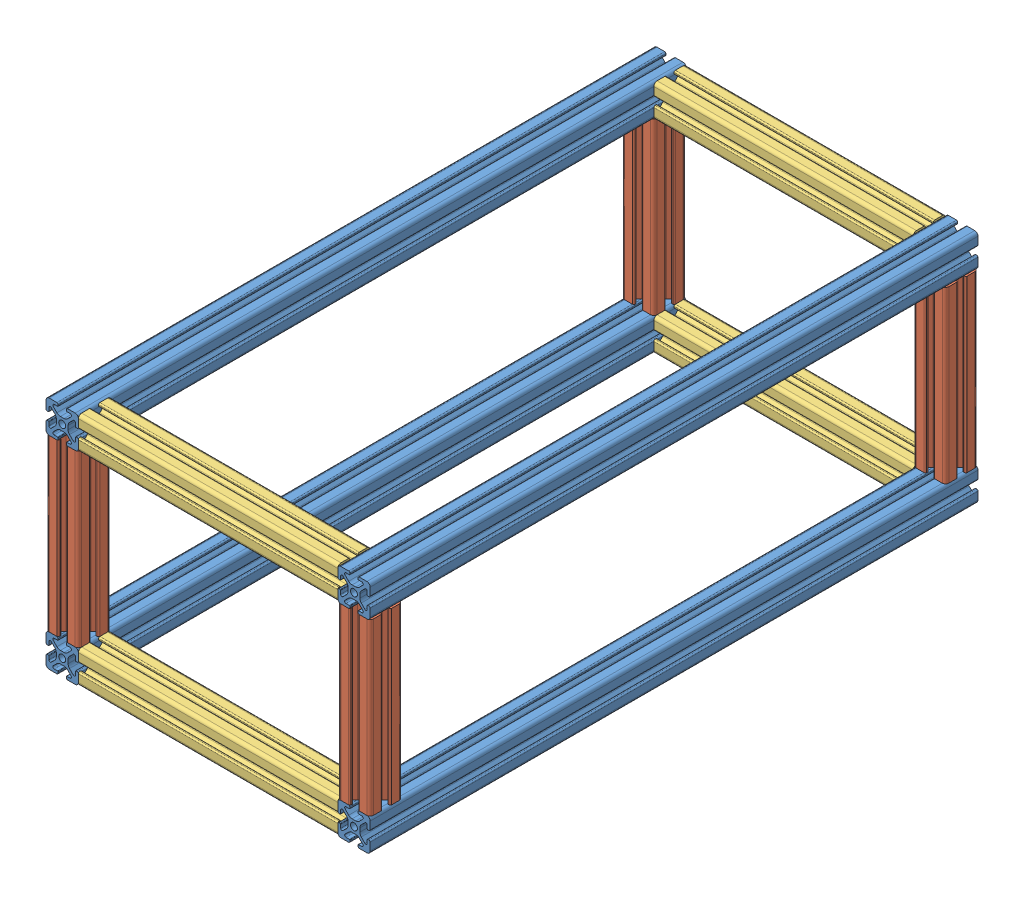
SolidWorks assembly UOR23-LYF-1-A-001, configuration Default. Lengths in mm.
Overall size (199.98 144.98 375).
12 component instances, 3 part files, 39 mates.
Components (placement in the parent):
- UOR23-LYF-1-P-001-8: UOR23-LYF-1-P-001 [Default] at (-89.9949 -62.4949 0) size (19.99 19.99 375)
- UOR23-LYF-1-P-001-9: UOR23-LYF-1-P-001 [Default] at (-89.9949 62.4949 0) size (19.99 19.99 375)
- UOR23-LYF-1-P-002-1: UOR23-LYF-1-P-002 [Default] at (-89.9949 0 177.5051) x (1 0 0) z (0 -1 0) size (19.99 19.99 105)
- UOR23-LYF-1-P-003-1: UOR23-LYF-1-P-003 [Default] at (0 -62.4949 177.5051) x (0 0 1) z (-1 0 0) size (19.99 19.99 160)
- UOR23-LYF-1-P-003-4: UOR23-LYF-1-P-003 [Default] at (0 -62.4949 -177.5051) x (0 0 -1) z (1 0 0) size (19.99 19.99 160)
- UOR23-LYF-1-P-002-2: UOR23-LYF-1-P-002 [Default] at (-89.9949 0 -177.5051) x (1 0 0) z (0 1 0) size (19.99 19.99 105)
- UOR23-LYF-1-P-002-3: UOR23-LYF-1-P-002 [Default] at (89.9949 0 -177.5051) x (-1 0 0) z (0 -1 0) size (19.99 19.99 105)
- UOR23-LYF-1-P-001-10: UOR23-LYF-1-P-001 [Default] at (89.9949 62.4949 0) x (-1 0 0) z (0 0 -1) size (19.99 19.99 375)
- UOR23-LYF-1-P-002-4: UOR23-LYF-1-P-002 [Default] at (89.9949 0 177.5051) x (-1 0 0) z (0 1 0) size (19.99 19.99 105)
- UOR23-LYF-1-P-001-11: UOR23-LYF-1-P-001 [Default] at (89.9949 -62.4949 0) x (-1 0 0) z (0 0 -1) size (19.99 19.99 375)
- UOR23-LYF-1-P-003-6: UOR23-LYF-1-P-003 [Default] at (0 62.4949 177.5051) x (0 1 0) z (1 0 0) size (19.99 19.99 160)
- UOR23-LYF-1-P-003-7: UOR23-LYF-1-P-003 [Default] at (0 62.4949 -177.5051) x (0 0 -1) z (1 0 0) size (19.99 19.99 160)
Mates (geometry in assembly coordinates):
- Coincident1: coincident anti-aligned: plane of UOR22-ARM-3-P-001-4 through (-97.9832 -52.5 187.5) normal (0 1 0); plane of UOR22-ARM-3-P-002-1 through (-91.1283 -52.5 184.1302) normal (0 -1 0)
- Coincident2: coincident aligned: plane of UOR22-ARM-3-P-001-4 through (-91.1283 -55.8698 187.5) normal (0 0 1); plane of UOR22-ARM-3-P-002-1 through (-82.0066 -52.5 187.5) normal (0 0 1)
- Coincident3: coincident aligned: plane of UOR22-ARM-3-P-001-4 through (-80 -54.5066 187.5) normal (1 0 0); plane of UOR22-ARM-3-P-002-1 through (-80 -52.5 185.4934) normal (1 0 0)
- Coincident4: coincident anti-aligned: plane of UOR22-ARM-3-P-001-4 through (-80 -70.4832 187.5) normal (1 0 0); plane of UOR22-ARM-3-P-003-1 through (-80 -55.8698 176.3717) normal (-1 0 0)
- Coincident5: coincident aligned: plane of UOR22-ARM-3-P-001-4 through (-91.1283 -55.8698 187.5) normal (0 0 1); plane of UOR22-ARM-3-P-003-1 through (-80 -70.4832 187.5) normal (0 0 1)
- Coincident6: coincident aligned: plane of UOR22-ARM-3-P-001-4 through (-82.0066 -72.4898 187.5) normal (0 -1 0); plane of UOR22-ARM-3-P-003-1 through (-80 -72.4898 185.4934) normal (0 -1 0)
- Coincident10: coincident aligned: plane of UOR22-ARM-3-P-001-7 through (-91.1283 69.12 187.5) normal (0 0 1); plane of UOR22-ARM-3-P-002-1 through (-97.9832 -52.5 187.5) normal (0 0 1)
- Coincident11: coincident anti-aligned: plane of UOR22-ARM-3-P-001-7 through (-97.9832 52.5 187.5) normal (0 -1 0); plane of UOR22-ARM-3-P-002-1 through (-91.1283 52.5 184.1302) normal (0 1 0)
- Coincident12: coincident aligned: plane of UOR22-ARM-3-P-001-7 through (-80 54.5066 187.5) normal (1 0 0); plane of UOR22-ARM-3-P-002-1 through (-80 -52.5 185.4934) normal (1 0 0)
- Coincident13: coincident aligned: plane of UOR22-ARM-3-P-001-4 through (-89.9949 -62.4949 0) normal (0 0 1)
- Coincident14: coincident anti-aligned: plane of UOR22-ARM-3-P-002-1 through (-89.9949 0 177.5051) normal (0 -1 0)
- Coincident15: coincident anti-aligned: plane of UOR22-ARM-3-P-003-1 through (0 -62.4949 177.5051) normal (-1 0 0)
- Coincident16: coincident anti-aligned: plane of UOR22-ARM-3-P-001-8 through (99.9898 54.5066 -187.5) normal (1 0 0); plane of UOR22-LYF-1-P-004_Front_Panel-1 through (99.9898 -10.0102 0) normal (-1 0 0)
- Width1: width aligned: plane of UOR22-LYF-1-P-004_Front_Panel-1 through (99.9898 -92.5102 -210) normal (0 0 -1); plane of UOR22-LYF-1-P-004_Front_Panel-1 through (99.9898 -92.5102 210) normal (0 0 1); plane of UOR22-ARM-3-P-002-3 through (97.9832 -52.5 -187.5) normal (0 0 -1); plane of UOR22-ARM-3-P-002-4 through (97.9832 52.5 187.5) normal (0 0 1)
- Coincident17: coincident aligned: plane of UOR22-LYF-1-P-004_Front_Panel-1 through (99.9898 72.4898 -210) normal (0 1 0); plane of UOR22-ARM-3-P-001-8 through (97.9832 72.4898 -187.5) normal (0 1 0)
- Coincident18: coincident anti-aligned: plane of UOR22-ARM-3-P-001-7 through (-82.0066 72.4898 187.5) normal (0 1 0); plane of UOR22-LYF-1-P-005_Top_Panel-1 through (-0.0102 72.4898 0) normal (0 -1 0)
- Coincident19: coincident anti-aligned: plane of UOR22-LYF-1-P-005_Top_Panel-1 through (-0.0102 72.4898 0) normal (0 0 -1)
- Coincident20: coincident anti-aligned: plane of UOR22-LYF-1-P-004_Front_Panel-1 through (99.9898 -10.0102 0) normal (-1 0 0); plane of UOR22-LYF-1-P-005_Top_Panel-1 through (99.9898 74.0778 -210) normal (1 0 0)
- Coincident21: coincident anti-aligned: plane of UOR22-ARM-3-P-001-8 through (80 54.5066 -187.5) normal (-1 0 0); plane of UOR22-ARM-3-P-003-6 through (80 61.3615 184.1302) normal (1 0 0)
- Coincident22: coincident aligned: plane of UOR22-ARM-3-P-001-8 through (82.0066 52.5 -187.5) normal (0 -1 0); plane of UOR22-ARM-3-P-003-6 through (80 52.5 185.4934) normal (0 -1 0)
- Distance1: distance = 0 mm aligned: plane of UOR22-ARM-3-P-003-6 through (80 70.4832 187.5) normal (0 0 1); plane of UOR22-ARM-3-P-001-8 through (91.1283 69.12 187.5) normal (0 0 1)
- Coincident24: coincident anti-aligned: plane of UOR22-ARM-3-P-001-8 through (80 54.5066 -187.5) normal (-1 0 0); plane of UOR22-ARM-3-P-003-7 through (80 69.12 -176.3717) normal (1 0 0)
- Coincident26: coincident aligned: plane of UOR22-LYF-1-P-001-7 through (-91.1283 69.12 -187.5) normal (0 0 -1); plane of UOR22-ARM-3-P-003-7 through (80 54.5066 -187.5) normal (0 0 -1)
- Coincident27: coincident aligned: plane of UOR22-LYF-1-P-001-9 through (97.9832 52.5 -187.5) normal (0 -1 0); plane of UOR22-ARM-3-P-003-7 through (80 52.5 -185.4934) normal (0 -1 0)
- Coincident28: coincident anti-aligned: plane of UOR22-LYF-1-P-001-10 through (82.0066 -52.5 -187.5) normal (0 1 0); plane of UOM20-7A000-1/UOM20-7P027-1 through (-5.2932 -52.5 108.4) normal (0 -1 0)
- Coincident29: coincident aligned: plane of UOR22-LYF-1-P-001-10 through (99.9898 -54.5066 -187.5) normal (1 0 0); plane of UOM20-7A000-1/UOM20-7P027-1 through (99.9898 -49.198 108.4) normal (1 0 0)
- Width2: width aligned: plane of UOM20-7A000-1/UOM20-7P027-1 through (-5.2932 -49.198 -188.41) normal (0 0 -1); plane of UOR22-LYF-1-P-003-4 through (-5.2932 -49.198 188.41) normal (0 0 1); plane of UOM20-7A000-1/UOM20-7P027-1 through (80 -54.5066 -187.5) normal (0 0 -1); plane of UOR22-LYF-1-P-003-1 through (-80 -54.5066 187.5) normal (0 0 1)
- Coincident30: coincident anti-aligned: plane of UOR22-LYF-1-P-001-9 through (99.9898 70.4832 -187.5) normal (1 0 0); plane of UOM20-7A002-1/UOM20-7P011-1 through (99.9898 52.4898 132.5102) normal (-1 0 0)
- Concentric1: concentric aligned: cylinder of UOM20-7A000-1/UOM20-7P027-1 through (-5.2932 -52.5 0) axis (0 1 0) radius 20.32; cylinder of Motor Housing assembly-1/Chamber -outlet-1 through (-5.2932 48.3148 0) axis (0 1 0) radius 10
- Parallel1: parallel anti-aligned: plane of Motor Housing assembly-1 through (-5.2932 240.4898 0) normal (-1 0 0)
- Distance2: distance = 170 mm aligned: plane of Motor Housing assembly-1/Motor housing-1 through (-5.2932 242.4898 0) normal (0 1 0); plane of UOR22-LYF-1-P-001-7 through (-82.0066 72.4898 187.5) normal (0 1 0)
- Coincident31: coincident anti-aligned: plane of UOR22-LYF-1-P-001-9 through (97.9832 72.4898 -187.5) normal (0 1 0); plane of UOM20-7A002-1/UOM20-7P011-1 through (119.9898 72.4898 132.5102) normal (0 -1 0)
- Coincident32: coincident anti-aligned: plane of UOR22-LYF-1-P-003-6 through (80 70.4832 167.5102) normal (0 0 -1); plane of UOM20-7A002-1/UOM20-7P011-1 through (119.9898 72.4898 167.5102) normal (0 0 1)
- Coincident33: coincident anti-aligned: plane of UOR22-LYF-1-P-001-9 through (99.9898 70.4832 -187.5) normal (1 0 0); plane of UOR22-LYF-1-P-006-1 through (99.9898 -0.0002 0) normal (-1 0 0)
- Coincident34: coincident aligned: plane of UOR22-LYF-1-P-001-9 through (82.0066 72.4898 -187.5) normal (0 1 0); plane of UOR22-LYF-1-P-006-1 through (99.9898 72.4898 187.5) normal (0 1 0)
- Coincident35: coincident aligned: plane of UOR22-LYF-1-P-002-4 through (97.9832 52.5 187.5) normal (0 0 1); plane of UOR22-LYF-1-P-006-1 through (99.9898 -72.4902 187.5) normal (0 0 1)
- Coincident36: coincident aligned: plane of UOR22-LYF-1-P-003-7 through (80 70.4832 -187.5) normal (0 0 -1); plane of UOR22-LYF-1-P-007-1 through (-44.9902 74.0773 -187.5) normal (0 0 -1)
- Coincident37: coincident anti-aligned: plane of UOR22-LYF-1-P-001-9 through (82.0066 72.4898 -187.5) normal (0 1 0); plane of UOR22-LYF-1-P-007-1 through (27.4998 72.4898 0) normal (0 -1 0)
- Coincident38: coincident: line of UOR22-LYF-1-P-006-1 through (99.9898 -72.4902 -187.5) axis (0 1 0); plane of UOR22-LYF-1-P-007-1 through (99.9898 74.0773 187.5) normal (1 0 0)
